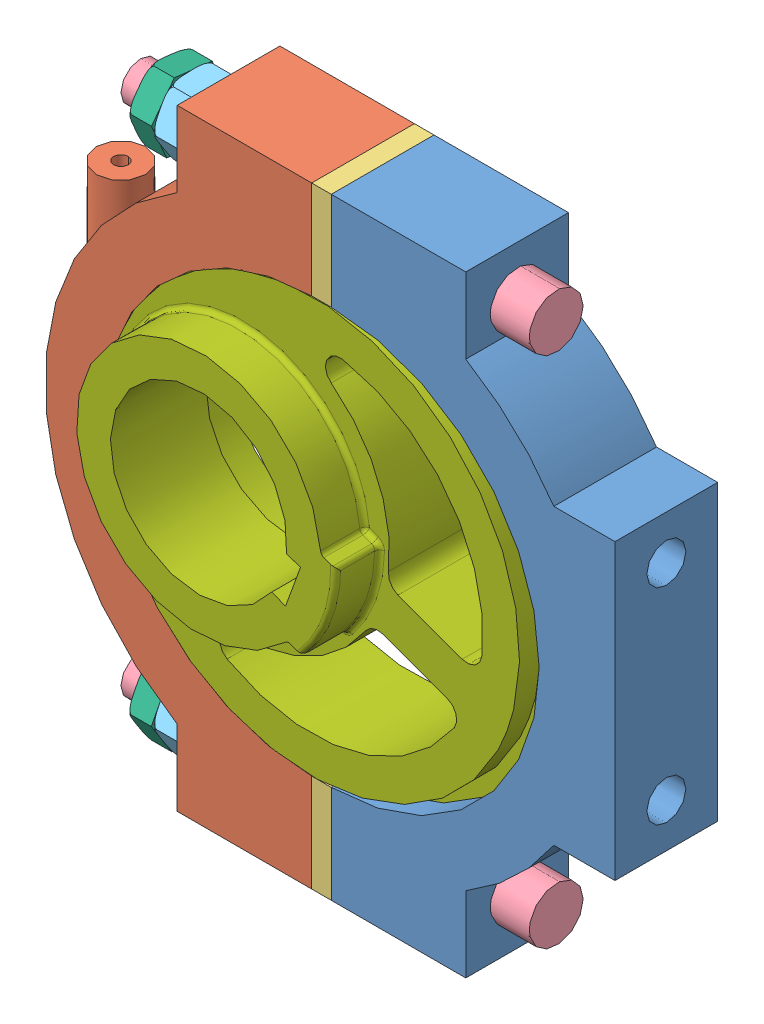
SolidWorks assembly Assem1, configuration Default. Lengths in mm.
Overall size (240.67 252.13 61.01).
11 component instances, 7 part files, 23 mates.
Components (placement in the parent):
- Part1-1: Part1 [Default] at (-94.1555 86.4242 -2.8888) size (116 250 42)
- Part2-1: Part2 [Default] at (-102.1555 86.4242 39.1112) x (-1 0 0) z (0 0 -1) size (109 250 42)
- Part5 shim-1: Part5 shim [Default] at (-102.1555 95.6758 -6.9007) x (0 0 -1) z (1 0 0) size (42 40 8)
- Part5 shim-3: Part5 shim [Default] at (-94.1555 -92.8275 -6.9007) x (0 0 -1) z (-1 0 0) size (42 40 8)
- Part6 bolt-1: Part6 bolt [Default] at (-23.1555 106.4242 18.1112) x (0 0 1) z (-1 0 0) size (22 22 170)
- Part6 bolt-2: Part6 bolt [Default] at (-23.1555 -103.5758 18.1112) x (0 0 1) z (-1 0 0) size (22 22 170)
- Part3 nut-1: Part3 nut [Default] at (-157.1555 -103.5758 18.1112) x (0 0 1) z (-1 0 0) size (32.9 29.43 17.91)
- Part3 nut-2: Part3 nut [Default] at (-157.1555 106.4242 18.1112) x (0 0 1) z (-1 0 0) size (32.9 29.43 17.91)
- Part4 lock nut-1: Part4 lock nut [Default] at (-173.1555 106.4242 18.1112) x (0 -0.774753 0.632264) z (-1 0 0) size (33.01 29.55 11.95)
- Part4 lock nut-2: Part4 lock nut [Default] at (-173.1555 -103.5758 18.1112) x (0 0 1) z (-1 0 0) size (33.01 29.55 11.95)
- Part7 sheave projection-1: Part7 sheave projection [Default] at (-102.1555 1.4242 18.1112) x (0.939505 -0.342535 0) z (0 0 1) size (182 182 60.13)
Mates (geometry in assembly coordinates):
- Concentric1: concentric anti-aligned: cylinder of Part1-1 through (302.8445 106.4242 18.1112) axis (-1 0 0) radius 8; cylinder of Part2-1 through (-499.1555 106.4242 18.1112) axis (1 0 0) radius 8
- Coincident8: coincident anti-aligned: plane of Part1-1 through (-94.1555 86.4242 39.1112) normal (-1 0 0); plane of Part5 shim-1 through (-94.1555 95.6758 -6.9007) normal (1 0 0)
- Concentric4: concentric aligned: cylinder of Part1-1 through (302.8445 106.4242 18.1112) axis (-1 0 0) radius 8; cylinder of Part5 shim-1 through (-94.1555 106.4242 18.1112) axis (-1 0 0) radius 8
- Concentric5: concentric anti-aligned: cylinder of Part1-1 through (302.8445 -103.5758 18.1112) axis (-1 0 0) radius 8; cylinder of Part5 shim-3 through (-102.1555 -103.5758 18.1112) axis (1 0 0) radius 8
- Coincident13: coincident anti-aligned: plane of Part1-1 through (-94.1555 86.4242 39.1112) normal (-1 0 0); plane of Part5 shim-3 through (-94.1555 -92.8275 -6.9007) normal (1 0 0)
- Tangent1: tangent anti-aligned: cylinder of Part1-1 through (-94.1555 1.4242 39.1112) axis (0 0 -1) radius 85; plane of Part5 shim-3 through (-102.1555 -83.5758 -6.9007) normal (0 1 0)
- Concentric6: concentric anti-aligned: cylinder of Part2-1 through (-499.1555 106.4242 18.1112) axis (1 0 0) radius 8; cylinder of Part5 shim-1 through (-94.1555 106.4242 18.1112) axis (-1 0 0) radius 8
- Concentric7: concentric aligned: cylinder of Part2-1 through (-499.1555 -103.5758 18.1112) axis (1 0 0) radius 8; cylinder of Part5 shim-3 through (-102.1555 -103.5758 18.1112) axis (1 0 0) radius 8
- Coincident14: coincident anti-aligned: plane of Part2-1 through (-102.1555 86.4242 -2.8888) normal (1 0 0); plane of Part5 shim-3 through (-102.1555 -92.8275 -6.9007) normal (-1 0 0)
- Concentric8: concentric anti-aligned: cylinder of Part1-1 through (302.8445 106.4242 18.1112) axis (-1 0 0) radius 8; cylinder of Part6 bolt-1 through (-151.1555 106.4242 18.1112) axis (1 0 0) radius 8
- Coincident15: coincident anti-aligned: plane of Part1-1 through (-39.1555 86.4242 39.1112) normal (1 0 0); plane of Part6 bolt-1 through (-39.1555 106.4242 18.1112) normal (-1 0 0)
- Concentric9: concentric anti-aligned: cylinder of Part1-1 through (302.8445 -103.5758 18.1112) axis (-1 0 0) radius 8; cylinder of Part6 bolt-2 through (-151.1555 -103.5758 18.1112) axis (1 0 0) radius 8
- Coincident16: coincident anti-aligned: plane of Part1-1 through (-39.1555 86.4242 39.1112) normal (1 0 0); plane of Part6 bolt-2 through (-39.1555 -103.5758 18.1112) normal (-1 0 0)
- Coincident17: coincident anti-aligned: plane of Part2-1 through (-157.1555 86.4242 -2.8888) normal (-1 0 0); plane of Part3 nut-2 through (-157.1555 106.4242 18.1112) normal (1 0 0)
- Concentric10: concentric aligned: circle of Part6 bolt-1; circle of Part3 nut-2
- Concentric11: concentric aligned: circle of Part6 bolt-1; circle of Part4 lock nut-1
- Coincident18: coincident anti-aligned: plane of Part3 nut-2 through (-173.1555 106.4242 18.1112) normal (-1 0 0); plane of Part4 lock nut-1 through (-173.1555 106.4242 18.1112) normal (1 0 0)
- Concentric12: concentric aligned: circle of Part6 bolt-2; circle of Part3 nut-1
- Coincident19: coincident anti-aligned: plane of Part2-1 through (-157.1555 86.4242 -2.8888) normal (-1 0 0); plane of Part3 nut-1 through (-157.1555 -103.5758 18.1112) normal (1 0 0)
- Concentric13: concentric aligned: circle of Part6 bolt-2; circle of Part4 lock nut-2
- Coincident20: coincident anti-aligned: plane of Part3 nut-1 through (-173.1555 -103.5758 18.1112) normal (-1 0 0); plane of Part4 lock nut-2 through (-173.1555 -103.5758 18.1112) normal (1 0 0)
- Concentric14: concentric anti-aligned: cylinder of Part2-1 through (-102.1555 1.4242 -2.8888) axis (0 0 1) radius 85; cylinder of Part7 sheave projection-1 through (-102.1555 1.4242 30.1112) axis (0 0 -1) radius 91
- Coincident21: coincident aligned: plane of Part1-1 through (-94.1555 86.4242 39.1112) normal (0 0 1); plane of Part7 sheave projection-1 through (-102.1555 1.4242 39.1112) normal (0 0 1)
